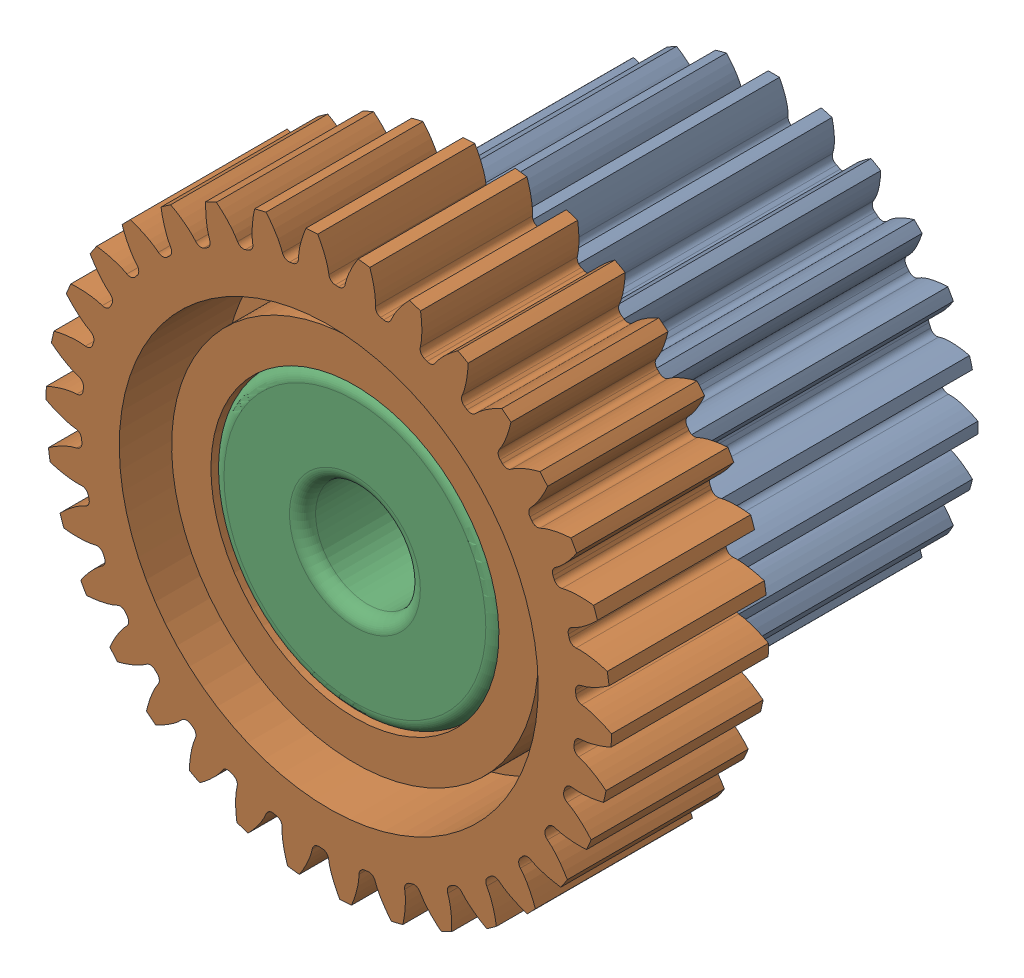
SolidWorks assembly Roue-dentée-2, configuration Défaut. Lengths in mm.
Overall size (28.58 28.61 17).
4 component instances, 3 part files, 6 mates.
Components (placement in the parent):
- ENG-D-24-6-1: ENG-D-24-6 [Configuration] at origin size (15.6 15.6 11)
- ENG-D-34-6-1: ENG-D-34-6 [Configuration] at (0 0 17) x (-0.909274 -0.416199 0) z (0 0 -1) size (21.54 21.6 6)
- Coussinet-1: Coussinet [Défaut] at (0 0 12) size (11 11 4)
- Coussinet-2: Coussinet [Défaut] at origin size (11 11 4)
Mates (geometry in assembly coordinates):
- Coïncidente1: coincident anti-aligned: plane of ENG-D-24-6-1 through (-0.5177 6.4292 11) normal (0 0 1); plane of ENG-D-34-6-1 through (-3.401 8.8168 11) normal (0 0 -1)
- Coïncidente2: coincident anti-aligned: axis of ENG-D-24-6-1 through (0 0 11) axis (0 0 -1); axis of ENG-D-34-6-1 through (0 0 13) axis (0 0 1)
- Coïncidente4: coincident anti-aligned: plane of ENG-D-34-6-1 through (0 0 12) normal (0 0 1); plane of Coussinet-1 through (0 0 12) normal (0 0 -1)
- Coïncidente5: coincident aligned: axis of ENG-D-24-6-1 through (0 0 11) axis (0 0 -1); axis of Coussinet-1 through (0 0 15.5) axis (0 0 -1)
- Coïncidente6: coincident anti-aligned: plane of ENG-D-24-6-1 through (0 0 4) normal (0 0 -1); plane of Coussinet-2 through (0 0 4.75) normal (0 0 1)
- Coïncidente7: coincident aligned: axis of ENG-D-24-6-1 through (0 0 11) axis (0 0 -1); axis of Coussinet-2 through (0 0 3.5) axis (0 0 -1)
